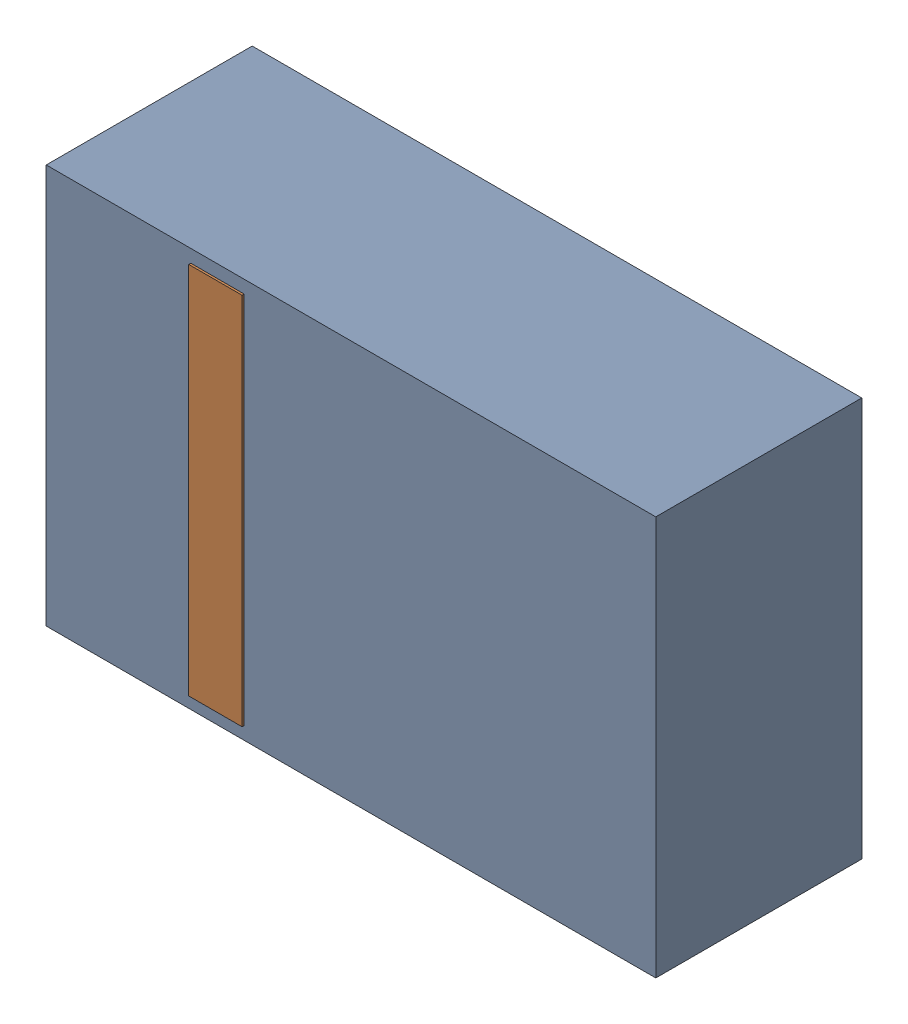
SolidWorks assembly D25, configuration Default. Lengths in mm.
Overall size (2.9 1.9 0.99).
4 component instances, 2 part files, 0 mates.
Components (placement in the parent):
- 905269392-1: 905269392 [Default] at (152.4 61.341 0) size (2.9 1.9 0.98)
  - Extruded_5-1: Extruded_5 [Default] at origin size (2.9 1.9 0.98)
- 905269800-1: 905269800 [Default] at (151.765 61.341 0.95) size (0.25 1.78 0.04)
  - Extruded_6-1: Extruded_6 [Default] at origin size (0.25 1.78 0.04)
